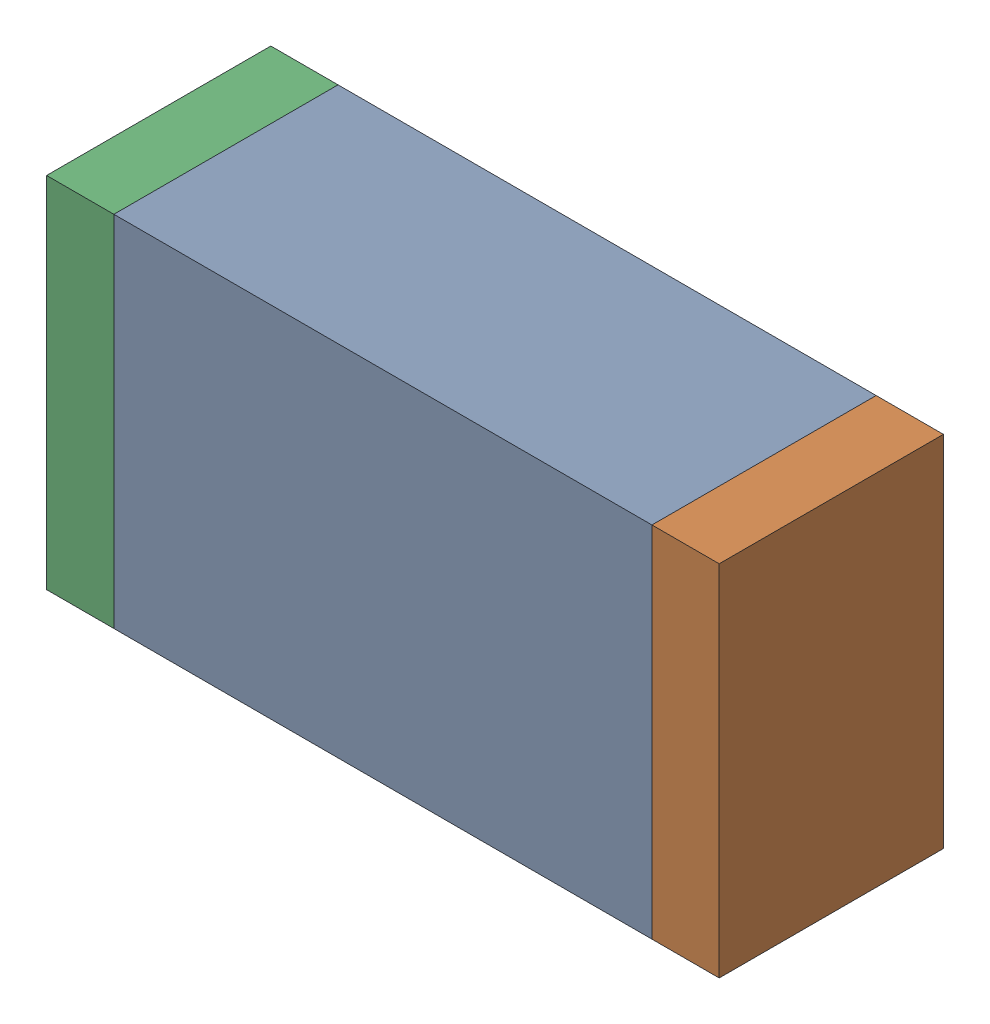
SolidWorks assembly C60, configuration Default. Lengths in mm.
Overall size (1.5 0.8 0.5).
6 component instances, 2 part files, 0 mates.
Components (placement in the parent):
- 836752368-1: 836752368 [Default] at (115.15 52.55 0) size (1.2 0.8 0.5)
  - Extruded-1: Extruded [Default] at origin size (1.2 0.8 0.5)
- 836752496-1: 836752496 [Default] at (115.825 52.55 0) size (0.15 0.8 0.5)
  - Extruded_2-1: Extruded_2 [Default] at origin size (0.15 0.8 0.5)
- 836752496-2: 836752496 [Default] at (114.475 52.55 0) size (0.15 0.8 0.5)
  - Extruded_2-1: Extruded_2 [Default] at origin size (0.15 0.8 0.5)
